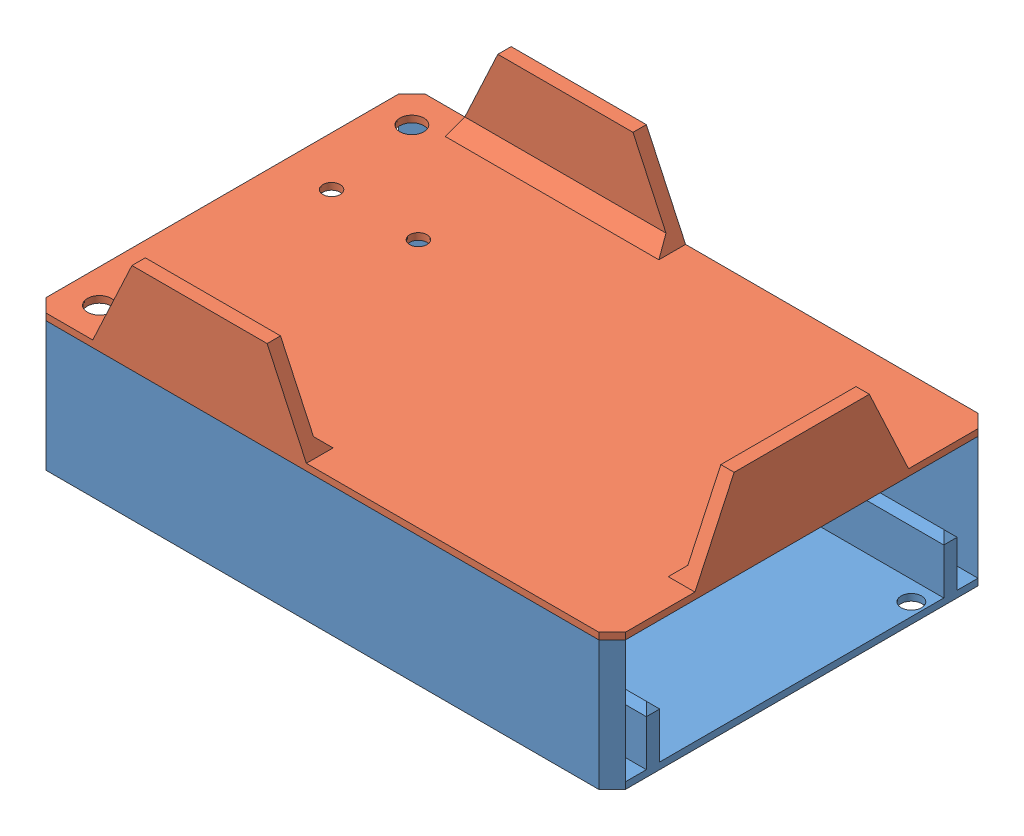
SolidWorks assembly Assem1, configuration Default. Lengths in mm.
Overall size (110.24 41.91 72.14).
2 component instances, 2 part files, 9 mates.
Components (placement in the parent):
- Radio Base Piece-1: Radio Base Piece [Default] at (1.609 59.9776 103.815) size (110.24 24.64 72.14)
- batteryboost plate-1: batteryboost plate [Default] at (1.609 84.6181 103.815) size (110.24 17.27 72.14)
Mates (geometry in assembly coordinates):
- Coincident1: coincident aligned: plane of Radio Base Piece-1 through (1.609 61.2476 103.815) normal (0 0 1); plane of Gps breakout section-1 through (1.609 83.5176 103.815) normal (0 0 1)
- Coincident2: coincident anti-aligned: plane of Radio Base Piece-1 through (1.609 84.6181 103.815) normal (0 1 0); plane of Gps breakout section-1 through (1.609 82.2476 103.815) normal (0 -1 0)
- Coincident3: coincident aligned: plane of Radio Base Piece-1 through (1.609 61.2476 103.815) normal (-1 0 0); plane of Gps breakout section-1 through (1.609 83.5176 103.815) normal (-1 0 0)
- Coincident4: coincident anti-aligned: plane of batteryboost plate-1 through (1.609 84.6181 103.815) normal (0 -1 0); plane of Gps breakout section-1 through (1.609 91.1376 103.815) normal (0 1 0)
- Coincident5: coincident aligned: plane of batteryboost plate-1 through (1.609 85.8881 103.815) normal (0 0 1); plane of Gps breakout section-1 through (1.609 83.5176 103.815) normal (0 0 1)
- Coincident6: coincident aligned: plane of batteryboost plate-1 through (1.609 85.8881 103.815) normal (-1 0 0); plane of Gps breakout section-1 through (1.609 83.5176 103.815) normal (-1 0 0)
- Coincident7: coincident anti-aligned: plane of Radio Base Piece-1 through (1.609 84.6181 103.815) normal (0 1 0); plane of batteryboost plate-1 through (1.609 84.6181 103.815) normal (0 -1 0)
- Coincident8: coincident aligned: plane of Radio Base Piece-1 through (1.609 61.2476 103.815) normal (0 0 1); plane of batteryboost plate-1 through (1.609 85.8881 103.815) normal (0 0 1)
- Coincident9: coincident aligned: plane of Radio Base Piece-1 through (111.845 61.2476 103.815) normal (1 0 0); plane of batteryboost plate-1 through (111.845 85.8881 103.815) normal (1 0 0)
